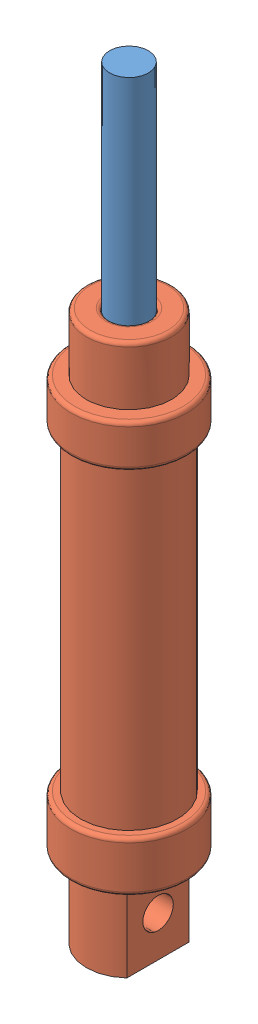
SolidWorks assembly Assem1, configuration Default. Lengths in mm.
Overall size (30 197 30).
2 component instances, 2 part files, 2 mates.
Components (placement in the parent):
- 5cm_rod-1: 5cm_rod [Default] at (-0.5707 24.5797 110.8902) x (-0.039364 0 0.999225) z (-0.999225 0 -0.039364) size (10 70 10)
- cylinder-1: cylinder [Default] at (-0.5707 -69.4203 110.8902) size (30 142 30)
Mates (geometry in assembly coordinates):
- Concentric1: concentric anti-aligned: cylinder of 5cm_rod-1 through (-0.5707 94.5797 110.8902) axis (0 -1 0) radius 5; cylinder of cylinder-1 through (-0.5707 19.5797 110.8902) axis (0 1 0) radius 5
- LimitDistance1: limit distance = 55 mm aligned: plane of 5cm_rod-1 through (-0.5707 94.5797 110.8902) normal (0 1 0); plane of cylinder-1 through (-0.5707 39.5797 110.8902) normal (0 1 0)
